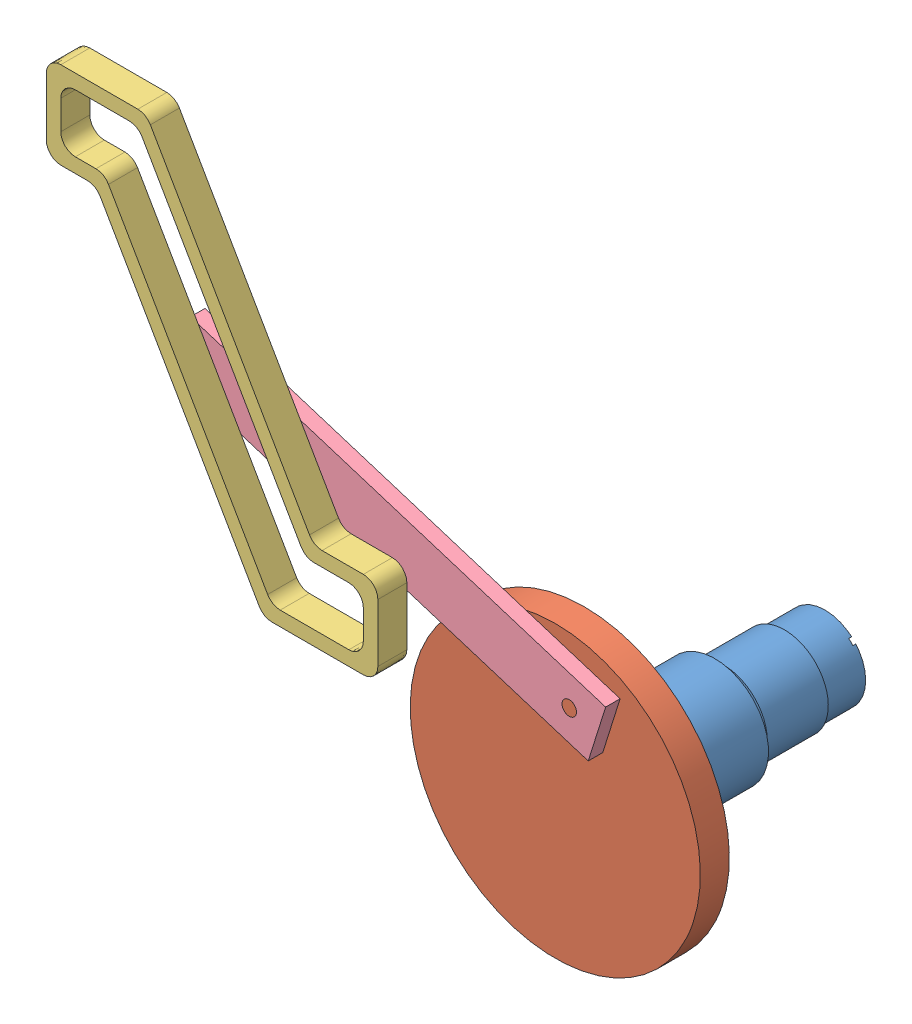
SolidWorks assembly test_grip, configuration Default. Lengths in mm.
Overall size (220.41 216.53 117.5).
4 component instances, 4 part files, 5 mates.
Components (placement in the parent):
- Motor - Johnson-1: Motor - Johnson [Default] at (39.025 65.6301 82.1809) x (0 0 -1) z (-1 0 0) size (97.5 37 37)
- linear_motion_disc-2: linear_motion_disc [Default] at (39.025 72.1253 102.1809) x (0 0 1) z (-0.928862 0.370426 0) size (20 100 100)
- travel_path-1: travel_path [Default] at (-27.1354 118.6875 122.1809) size (114.28 130 10)
- path_link2-1: path_link2 [Default] at (-8.1695 128.7623 117.1809) x (0.954024 -0.299731 0) z (0 0 1) size (150 20 5)
Mates (geometry in assembly coordinates):
- Concentric2: concentric aligned: cylinder of Motor - Johnson-1 through (39.025 72.1253 112.1809) axis (0 0 -1) radius 3; cylinder of linear_motion_disc-2 through (39.025 72.1253 112.1809) axis (0 0 -1) radius 50
- Coincident2: coincident aligned: plane of Motor - Johnson-1 through (39.025 72.1253 112.1809) normal (0 0 1); plane of linear_motion_disc-2 through (39.025 72.1253 112.1809) normal (0 0 1)
- Tangent1: tangent aligned: plane of travel_path-1 through (-38.6824 98.6875 132.1809) normal (0.866025 0.5 0); cylinder of path_link2-1 through (-70.1811 148.2448 122.1809) axis (0 0 -1) radius 2.5
- Coincident5: coincident anti-aligned: plane of travel_path-1 through (-27.1354 118.6875 122.1809) normal (0 0 -1); plane of path_link2-1 through (-8.1695 128.7623 122.1809) normal (0 0 1)
- Concentric5: concentric aligned: cylinder of linear_motion_disc-2 through (53.842 109.2798 122.1809) axis (0 0 -1) radius 2.5; cylinder of path_link2-1 through (53.842 109.2798 122.1809) axis (0 0 -1) radius 2.5
